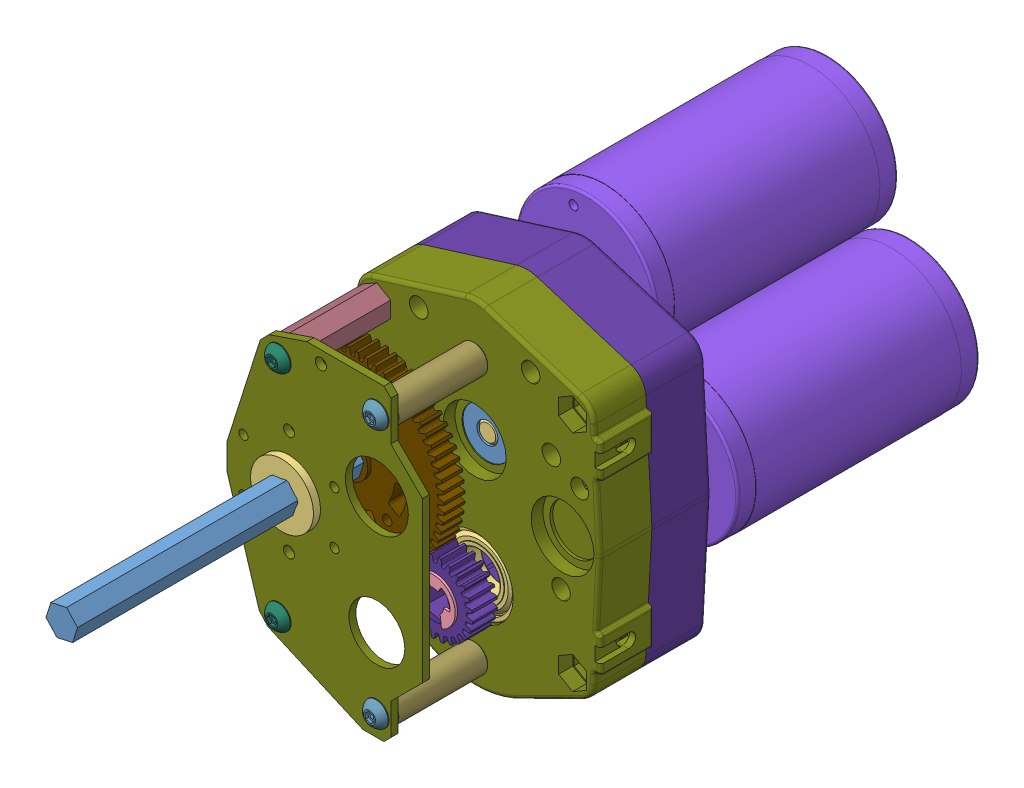
SolidWorks assembly 217-3269-STEP, configuration Default. Lengths in mm.
Overall size (164.35 174.72 312.65).
72 component instances, 40 part files, 0 mates.
Components (placement in the parent):
- 217-2733-1: 217-2733 [Default] at (0 53.4162 37.6682) x (0 0 1) z (-0.00054 -1 0) size (7.11 24.61 24.61)
- 217-2733-2: 217-2733 [Default] at (0 53.4162 7.9248) x (0 0 -1) z (-0.038475 0.99926 0) size (7.11 24.61 24.61)
- 217-2731-1: 217-2731 [Default] at (0 0 -0.0127) x (1 0 0) z (0 -1 0) size (31.12 7.94 31.12)
- 217-2789-1: 217-2789 [Default] at (0 0 43.2943) x (0 0 -1) z (0.998073 -0.062043 0) size (11.1 38.4 38.4)
- 217-2428-027 Rev1_97414A630-1: 217-2428-027 Rev1_97414A630 [Default] at (0 0 -6.5151) x (0 0 1) z (0.453751 0.891129 0) size (0.64 5.89 7.9)
- 217-2788_57155K375-1: 217-2788_57155K375 [Default] at (-0.0022 0.3376 -8.4201) x (0.971787 -0.235861 0) z (0 0 1) size (9.53 9.53 3.17)
- 217-2428-012 Rev3-1: 217-2428-012 Rev3 [Default] at (0 0 -40.386) size (63.5 22.23 2.29)
- 217-2428-027 Rev1_97414A630-2: 217-2428-027 Rev1_97414A630 [Default] at (0 0 -10.3251) x (0 0 1) z (-0.054891 -0.998492 0) size (0.64 5.89 7.9)
- 217-2428-005 Rev1-1: 217-2428-005 Rev1 [Default] at (25.4 0 -19.05) x (-0.557362 -0.83027 0) z (-0.83027 0.557362 0) size (7.33 38.98 6.35)
- 217-2428-005 Rev1-2: 217-2428-005 Rev1 [Default] at (-25.4 0 -19.05) x (0.667436 0.744667 0) z (0.744667 -0.667436 0) size (7.33 38.98 6.35)
- SCREW-832-0375-1: SCREW-832-0375 [Default] at (25.4 0 -42.5958) x (0 0 1) z (-0.875404 0.483392 0) size (11.73 7.92 7.92)
- SCREW-832-0375-2: SCREW-832-0375 [Default] at (-25.4 0 -42.5958) x (0 0 1) z (-0.966319 0.257347 0) size (11.73 7.92 7.92)
- SCREW-832-0375-3: SCREW-832-0375 [Default] at (25.4 0 5.3848) x (0 0 -1) z (1 0 0) size (11.73 7.92 7.92)
- SCREW-832-0375-4: SCREW-832-0375 [Default] at (-25.4 0 5.3848) x (0 0 -1) z (0.941463 -0.337115 0) size (11.73 7.92 7.92)
- SBS1_SBS-0632-0250-1: SBS1_SBS-0632-0250 [Default] at (15.494 0 -36.2458) x (0 0 -1) z (0.854303 -0.519775 0) size (8.57 6.68 6.65)
- SBS1_SBS-0632-0250-2: SBS1_SBS-0632-0250 [Default] at (-15.494 0 -36.2458) x (0 0 -1) z (0.854303 -0.519775 0) size (8.57 6.68 6.65)
- 217-2428-016 Rev2_Spur01-1: 217-2428-016 Rev2_Spur01 [Default] at (0 0 -3.6517) x (0.918689 -0.394983 0) z (0 0 1) size (40.67 40.74 13.3)
- 217-2428-018 Rev2-1: 217-2428-018 Rev2 [Default] at (-12.7 -21.997 -14.2875) x (0.866025 -0.5 0) z (0 0 1) size (41.28 25.4 6.92)
- 217-2788_57155K375-2: 217-2788_57155K375 [Default] at (-12.7 -21.997 -8.9535) x (-0.775754 -0.631035 0) z (0 0 -1) size (9.53 9.53 3.17)
- 217-2428-009 Rev1-1: 217-2428-009 Rev1 [Default] at (-3.6662 -34.925 -6.35) x (-0.470706 0.88229 0) z (0.88229 0.470706 0) size (7.33 13.58 6.35)
- 217-2428-009 Rev1-2: 217-2428-009 Rev1 [Default] at (-28.4129 -20.6375 -6.35) x (-0.555959 0.831209 0) z (0.831209 0.555959 0) size (7.33 13.58 6.35)
- SCREW-832-0250-1: SCREW-832-0250 [Default] at (-28.4129 -20.6375 -16.4973) x (0 0 1) z (-0.923728 -0.383049 0) size (8.56 7.92 7.92)
- SCREW-832-0375-5: SCREW-832-0375 [Default] at (-28.4129 -20.6375 5.3848) x (0 0 -1) z (-0.274582 -0.961564 0) size (11.73 7.92 7.92)
- SCREW-832-0375-6: SCREW-832-0375 [Default] at (-3.6662 -34.925 5.3848) x (0 0 -1) z (-0.826375 -0.56312 0) size (11.73 7.92 7.92)
- SCREW-832-0250-2: SCREW-832-0250 [Default] at (-3.6662 -34.925 -16.4973) x (0 0 1) z (-0.923728 -0.383049 0) size (8.56 7.92 7.92)
- 217-2614-001_12t-1: 217-2614-001_12t [Default] at (36.9798 39.6868 15.8623) x (0.996195 0.087156 0) z (0 0 1) size (18.29 18.29 19)
- 217-2761-001 rev1-1: 217-2761-001 rev1 [Default] at (36.6486 43.4723 16.1) x (-0.996195 -0.087156 0) z (0 0 1) size (2 2 20)
- 217-2761-001 rev1-2: 217-2761-001 rev1 [Default] at (-36.6486 43.4723 16.1) x (0.996195 -0.087156 0) z (0 0 1) size (2 2 20)
- 217-2614-001_12t-2: 217-2614-001_12t [Default] at (-36.9798 39.6868 15.8623) x (0.996195 -0.087156 0) z (0 0 1) size (18.29 18.29 19)
- 217-2614-001_12t-3: 217-2614-001_12t [Default] at (0 92.8624 15.8623) x (0.97459 0.223996 0) z (0 0 1) size (18.29 18.29 19)
- 217-2761-001 rev1-3: 217-2761-001 rev1 [Default] at (-0.8512 96.5658 16.1) x (0.97459 0.223996 0) z (0 0 1) size (2 2 20)
- 217-3195-002 rev1-1: 217-3195-002 rev1 [Default] at (0 0 50.546) x (-1 0 0) z (0 0 -1) size (114.31 152.24 24.96)
- 217-3195-001 Rev1-1: 217-3195-001 Rev1 [Default] at origin size (113.41 152.24 26.86)
- Nylock Nut_NNY2520-ZC-1: Nylock Nut_NNY2520-ZC [Default] at (48.8823 73.025 37.846) x (0 0.866025 -0.5) z (-1 0 0) size (12.85 11.89 7.62)
- Nylock Nut_NNY2520-ZC-2: Nylock Nut_NNY2520-ZC [Default] at (48.8823 -3.175 37.846) x (0 0 -1) z (-1 0 0) size (12.85 11.89 7.62)
- Nylock Nut_NNY2520-ZC-3: Nylock Nut_NNY2520-ZC [Default] at (44.45 85.725 7.8613) x (0 1 0) z (0 0 -1) size (12.85 11.89 7.62)
- NUT-832-NYLOCK-1: NUT-832-NYLOCK [Default] at (47.625 58.1787 5.3937) x (0.5 0.866025 0) z (-0.866025 0.5 0) size (10.2 5.86 8.12)
- NUT-832-NYLOCK-2: NUT-832-NYLOCK [Default] at (-47.625 58.1787 5.3937) x (-1 0 0) z (0 -1 0) size (10.2 5.86 8.12)
- SCREW-832-1750-1: SCREW-832-1750 [Default] at (-47.625 58.1787 47.0408) x (0 0 -1) z (-0.960822 -0.277167 0) size (46.66 7.92 7.92)
- SCREW-832-1750-2: SCREW-832-1750 [Default] at (47.625 58.1787 47.0408) x (0 0 -1) z (-0.960822 -0.277167 0) size (46.66 7.92 7.92)
- Nylock Nut_NNY2520-ZC-4: Nylock Nut_NNY2520-ZC [Default] at (44.45 -15.875 7.8613) x (0 1 0) z (0 0 -1) size (12.85 11.89 7.62)
- 217-2428-004 Rev3-1: 217-2428-004 Rev3 [Default] at (0 53.4162 22.7711) x (0.360537 -0.932745 0) z (0 0 1) size (11 9.53 43.92)
- SBS1_SBS-2520-1625SS-1: SBS1_SBS-2520-1625SS [Default] at (44.45 85.725 42.4688) x (0 0 -1) z (-0.251219 0.96793 0) size (45.3 11.22 11.17)
- SBS1_SBS-2520-1625SS-2: SBS1_SBS-2520-1625SS [Default] at (44.45 -15.875 42.4688) x (0 0 -1) z (-0.251219 0.96793 0) size (45.3 11.22 11.17)
- SBS1_SBS2520-1750-1: SBS1_SBS2520-1750 [Default] at (-44.45 85.725 7.4422) x (0 0 1) z (-0.994188 -0.107657 0) size (48.48 11.22 11.17)
- SBS1_SBS2520-1750-2: SBS1_SBS2520-1750 [Default] at (-44.45 -15.875 7.4422) x (0 0 1) z (-0.994188 -0.107657 0) size (48.48 11.22 11.17)
- 217-2428-021 Rev1-1: 217-2428-021 Rev1 [Default] at (0 53.4162 9.5123) x (0.451333 -0.892356 0) z (0 0 1) size (15.88 15.88 3.17)
- 217-2428-029 Rev1-1: 217-2428-029 Rev1 [Default] at (0 53.4162 36.957) x (0.999846 0.017557 0) z (0 0 1) size (15.88 15.88 1.12)
- 217-2000-1: 217-2000 [Default] at (0 92.8624 0) x (0 0 -1) z (0.97459 0.223996 0) size (150.2 64.01 64.01)
- 217-2000-2: 217-2000 [Default] at (-36.9798 39.6868 0) x (0 0 -1) z (0.996195 -0.087156 0) size (150.2 64.01 64.01)
- 217-2000-3: 217-2000 [Default] at (36.9798 39.6868 0) x (0 0 -1) z (0.996195 0.087156 0) size (150.2 64.01 64.01)
- E4P-X-250-X-D-D-D-X-1: E4P-X-250-X-D-D-D-X [Default] at (-12.7 -21.997 -14.2875) x (0.5 0.866025 0) z (-0.866025 0.5 0) size (24.87 14.38 22.9)
- 217-2711-001_50t-1: 217-2711-001_50t [Default] at (0 53.4162 17.4244) x (0.154138 0.988049 0) z (0 0 1) size (66.7 66.76 12.65)
- 217-3210-001 Rev1_30t-1: 217-3210-001 Rev1_30t [Default] at (0 53.4162 30.0736) x (0.778607 -0.627512 0) z (0 0 1) size (41.01 41.12 12.65)
- 217-3195-009 Rev1_wcd 2-1: 217-3195-009 Rev1_wcd 2 [Default] at (0 85.725 50.4952) x (-0.989159 -0.146851 0) z (0 0 1) size (12.7 12.7 41.27)
- 217-3195-006 Rev1_WCD-1: 217-3195-006 Rev1_WCD [Default] at (-44.45 85.725 44.1452) x (-0.5 -0.866025 0) z (0 0 1) size (12.7 14.66 47.62)
- 217-3195-006 Rev1_WCD-2: 217-3195-006 Rev1_WCD [Default] at (-44.45 -15.875 44.1452) x (0.5 -0.866025 0) z (0 0 1) size (12.7 14.66 47.62)
- Nylock Nut_NNY2520-ZC-5: Nylock Nut_NNY2520-ZC [Default] at (0 -31.75 45.0723) x (-0.5 0.866025 0) z (0 0 -1) size (12.85 11.89 7.62)
- Nylock Nut_NNY2520-ZC-6: Nylock Nut_NNY2520-ZC [Default] at (0 85.725 45.0723) x (-0.5 0.866025 0) z (0 0 -1) size (12.85 11.89 7.62)
- SBS1_SBS-2520-2250-1: SBS1_SBS-2520-2250 [Default] at (0 -31.75 98.298) x (0 0 -1) z (0.656286 -0.754513 0) size (61.18 11.22 11.17)
- SBS1_SBS2520-0625ZC-1: SBS1_SBS2520-0625ZC [Default] at (-44.45 85.725 98.298) x (0 0 -1) z (0.626272 -0.779605 0) size (19.57 11.22 11.17)
- SBS1_SBS2520-0625ZC-2: SBS1_SBS2520-0625ZC [Default] at (-44.45 -15.875 98.298) x (0 0 -1) z (0.880271 -0.474471 0) size (19.57 11.22 11.17)
- SBS1_SBS-2520-2250-2: SBS1_SBS-2520-2250 [Default] at (0 85.725 98.298) x (0 0 -1) z (0.323707 -0.946158 0) size (61.18 11.22 11.17)
- 217-3195-003 rev2-1: 217-3195-003 rev2 [Default] at (0 0 94.9452) size (88.62 139.7 3.17)
- 217-2704-001_24-1: 217-2704-001_24 [Default] at (-0.0127 0.0421 62.3062) x (-0.729505 0.683975 0) z (0 0 -1) size (33.29 33.29 12.65)
- 217-2715-001_64t-1: 217-2715-001_64t [Default] at (-39.878 35.5392 61.7541) x (0.954309 -0.29882 0) z (0 0 -1) size (84.3 84.3 12.65)
- 217-2617-003 Rev1-1: 217-2617-003 Rev1 [Default] at (-39.878 35.5392 121.8535) x (0.677046 -0.735941 0) z (0 0 1) size (14.66 12.7 152.4)
- 217-2743-1: 217-2743 [Default] at (-39.878 35.5392 49.1808) x (0 0 1) z (0.312889 -0.94979 0) size (7.94 28.58 28.58)
- 217-2734-1: 217-2734 [Default] at (-39.878 35.5392 98.1202) x (0.399009 0.916947 0) z (-0.916947 0.399009 0) size (31.12 7.94 31.12)
- 217-2617-004 Rev1_97431A340_grv-1: 217-2617-004 Rev1_97431A340_grv [Default] at (0 0 69.0626) x (0 0 1) z (-0.124043 -0.992277 0) size (1.07 20.42 18.58)
- 217-3195-009 Rev1_wcd 2-2: 217-3195-009 Rev1_wcd 2 [Default] at (0 -31.75 50.546) x (-0.989159 -0.146851 0) z (0 0 1) size (12.7 12.7 41.27)
- 217-2617-004 Rev1_97431A340_grv-2: 217-2617-004 Rev1_97431A340_grv [Default] at (-39.878 35.5392 54.8961) x (0 0 1) z (-0.124043 -0.992277 0) size (1.07 20.42 18.58)
